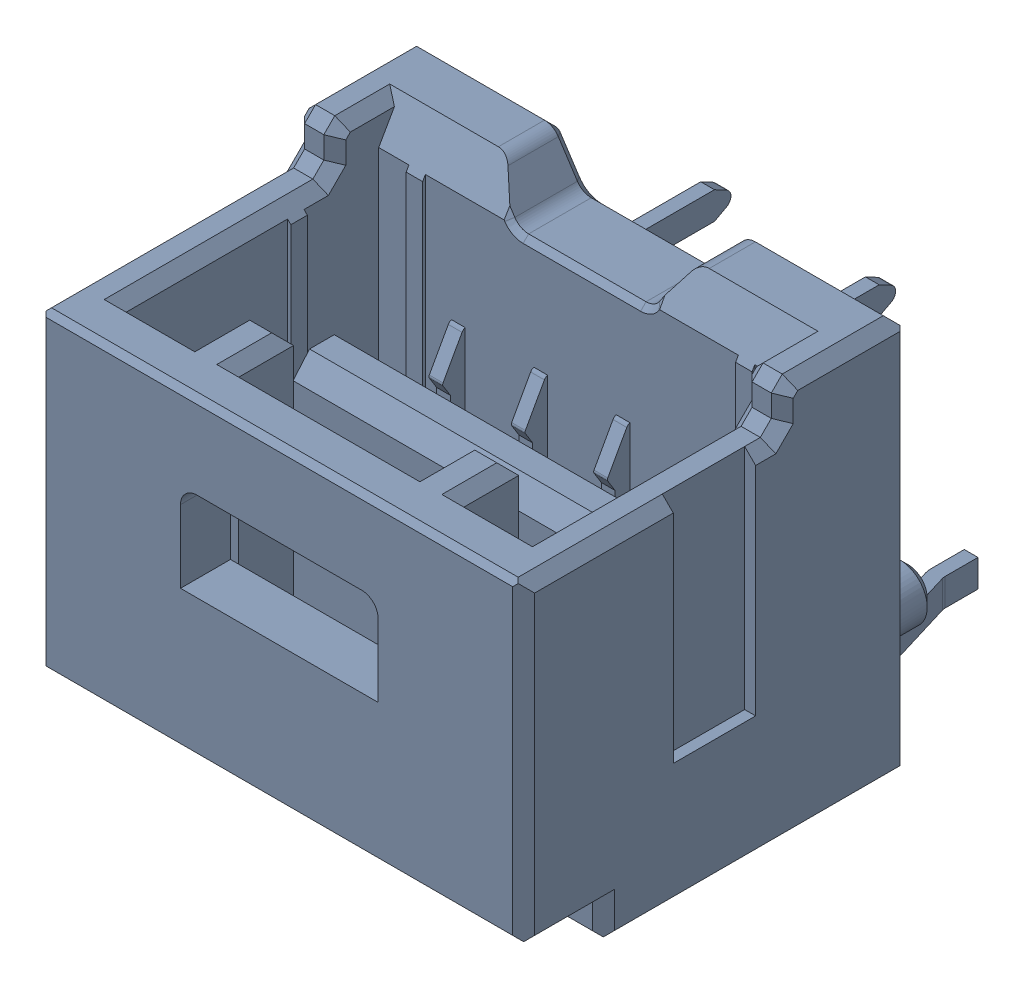
SolidWorks assembly J2, configuration Default. Lengths in mm.
Overall size (8.9 7.25 10.35).
2 component instances, 1 part files, 0 mates.
Components (placement in the parent):
- 5031750400-1: 5031750400 [Default] at (5.1969 6.2699 4.3628) x (1 0 0) z (0 -1 0) size (8.9 10.35 7.25)
  - Open CASCADE STEP translator 7.5 1.20.1.1-1: Open CASCADE STEP translator 7.5 1.20.1.1 [Default] at origin size (8.9 10.35 7.25)
